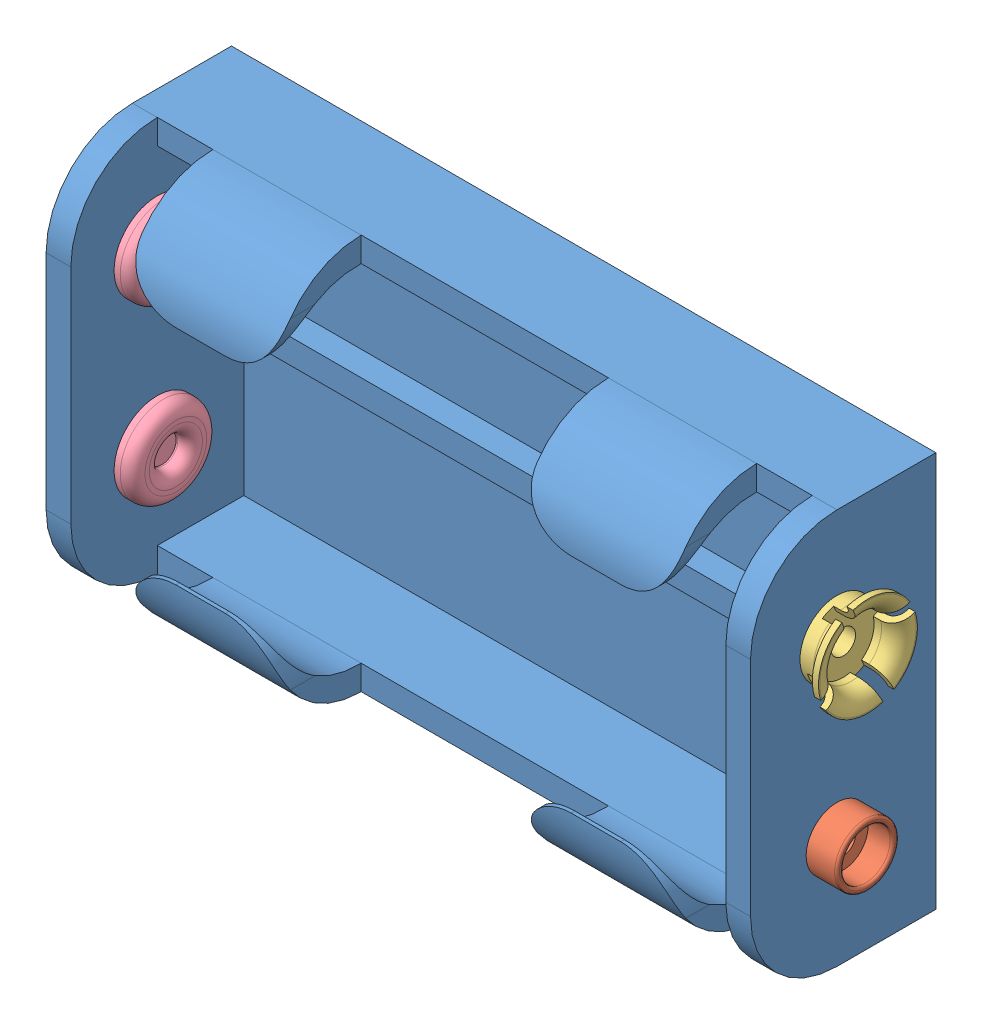
SolidWorks assembly Coupleur-2R6, configuration Défaut. Lengths in mm.
Overall size (59.59 32 15).
5 component instances, 4 part files, 0 mates.
Components (placement in the parent):
- Coupleur-2R6-corps-1: Coupleur-2R6-corps [Default] at origin size (57 32 15)
- Coupleur-2R6-contact-P-1: Coupleur-2R6-contact-P [Default] at (55.0562 9 9) x (-1 0 0) z (0 -0.517166 0.855885) size (6 6.67 6.67)
- Coupleur-2R6-contact-G-1: Coupleur-2R6-contact-G [Default] at (55.0562 23 9) x (-1 0 0) z (0 -0.418463 0.908234) size (6.09 7.94 7.94)
- Coupleur-2R6-contact-3: Coupleur-2R6-contact [Default] at (2 23 9) size (1.5 7 7)
- Coupleur-2R6-contact-4: Coupleur-2R6-contact [Default] at (2 9 9) size (1.5 7 7)
